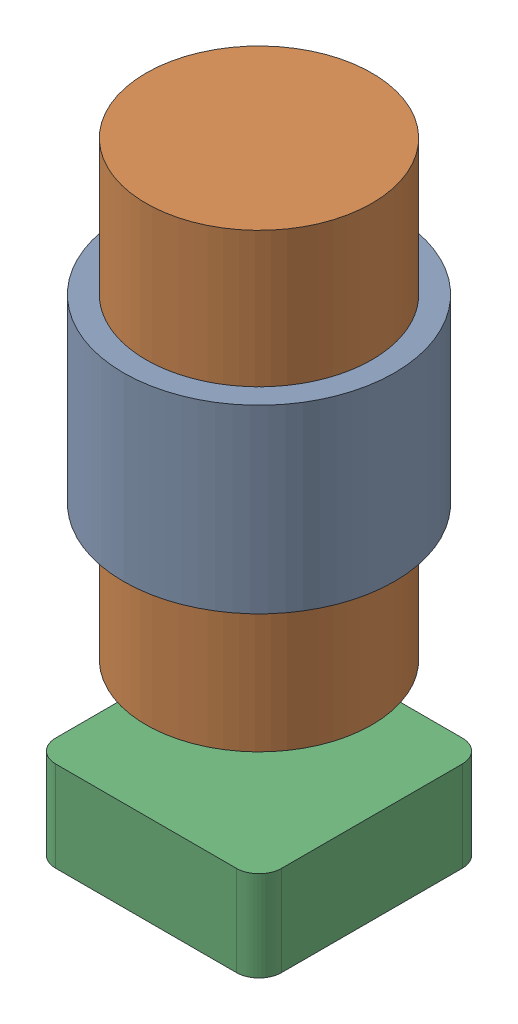
SolidWorks assembly COMSOL_CircularAssembly, configuration Default. Lengths in mm.
Overall size (0.6 1.38 0.6).
3 component instances, 3 part files, 5 mates.
Components (placement in the parent):
- COMSOL_CircularCoil-1: COMSOL_CircularCoil [Default] at (-0.0523 -0.0743 0.0781) size (0.6 0.4 0.6)
- COMSOL_CircularCore-1: COMSOL_CircularCore [Default] at (-0.0523 -0.3743 0.0781) x (0 0 -1) z (1 0 0) size (0.5 1 0.5)
- COMSOL_Magnet-1: COMSOL_Magnet [Default] at (0.1977 -0.5493 0.3281) x (0 0 -1) z (-1 0 0) size (0.5 0.2 0.5)
Mates (geometry in assembly coordinates):
- Concentric1: concentric aligned: circle of COMSOL_CircularCoil-1; circle of COMSOL_CircularCore-1
- Coincident2: coincident anti-aligned: line of COMSOL_CircularCoil-1 through (-0.3523 0.1257 0.0781) axis (1 0 0); line of COMSOL_CircularCore-1 through (0.1977 0.1257 0.0781) axis (-1 0 0)
- Concentric3: concentric: circle of COMSOL_CircularCore-1; circle of COMSOL_Magnet-1
- Parallel1: parallel: line of COMSOL_CircularCore-1 through (-0.3023 -0.3743 0.0781) axis (1 0 0); line of COMSOL_Magnet-1 through (0.1477 -0.8095 0.3281) axis (-1 0 0)
- Distance1: distance = 0.175 mm anti-aligned: plane of COMSOL_Magnet-1 through (0.1977 -0.5493 0.3281) normal (0 1 0); plane of COMSOL_CircularCore-1 through (-0.0523 -0.3743 0.0781) normal (0 -1 0)
